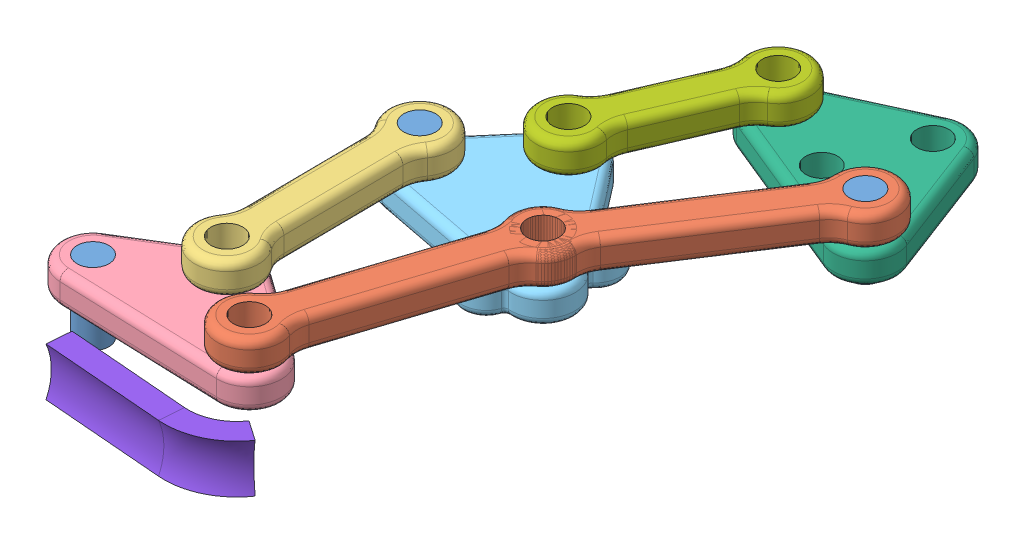
SolidWorks assembly Test, configuration Default. Lengths in mm.
Overall size (93.86 21.45 141.22).
11 component instances, 8 part files, 23 mates.
Components (placement in the parent):
- Pin-2: Pin [Default] at (17.2663 20.8923 103.6402) x (-0.850358 0 0.526205) z (-0.526205 0 -0.850358) size (6.6 14.85 6.6)
- Pin-5: Pin [Default] at (75.0993 20.8923 69.342) size (6.6 14.85 6.6)
- 7.3mmLink-1: 7.3mmLink [Default] at (52.0373 31.2673 104.85) x (0.544688 0 -0.838639) z (0.838639 0 0.544688) size (61.38 6.6 13.2)
- 6mmLink-3: 6mmLink [Default] at (17.5842 31.2673 138.9955) x (-0.008992 0 -0.99996) z (0.99996 0 -0.008992) size (53.43 6.6 13.2)
- 7.3mmLink-2: 7.3mmLink [Default] at (35.7914 31.2673 150.0215) x (0.30857 0 -0.951202) z (0.951202 0 0.30857) size (61.38 6.6 13.2)
- TriLink3-3: TriLink3 [Default] at (17.8182 24.6673 139.6408) x (0.852314 0 -0.52303) z (0.52303 0 0.852314) size (41.14 6.6 31.73)
- TriLink2-6: TriLink2 [Default] at (30.1841 24.6673 79.864) x (0.653306 0 -0.757094) z (0.757094 0 0.653306) size (35.81 6.6 41.11)
- TriLink1-5: TriLink1 [Default] at (68.8686 24.6673 41.0221) x (0.90935 0 -0.416033) z (0.416033 0 0.90935) size (37.33 6.6 37.28)
- Pin-6: Pin [Default] at (0.4822 14.2923 154.3938) x (0.997175 0 -0.075115) z (0.075115 0 0.997175) size (6.6 14.85 6.6)
- 5mmLink-4: 5mmLink [Default] at (33.0867 31.2673 83.4671) x (0.39569 0 -0.918384) z (0.918384 0 0.39569) size (46.2 6.6 13.2)
- Pad-1: Pad [Default] at (12.0164 27.9673 170.2645) x (0.996713 0 0.081009) z (-0.081009 0 0.996713) size (38.39 10 10)
Mates (geometry in assembly coordinates):
- Concentric9: concentric aligned: cylinder of Pin-5 through (75.0993 39.5673 69.342) axis (0 -1 0) radius 3.3; cylinder of 7.3mmLink-1 through (75.0993 39.5673 69.342) axis (0 -1 0) radius 3.3
- Coincident12: coincident aligned: plane of Pin-2 through (17.2663 39.5673 103.6402) normal (0 1 0); plane of 7.3mmLink-1 through (44.0533 39.5673 97.4525) normal (0 1 0)
- Concentric11: concentric aligned: cylinder of Pin-2 through (17.2663 39.5673 103.6402) axis (0 -1 0) radius 3.3; cylinder of 6mmLink-3 through (17.2663 39.5673 103.6402) axis (0 -1 0) radius 3.3
- Coincident13: coincident aligned: plane of Pin-2 through (17.2663 39.5673 103.6402) normal (0 1 0); plane of 6mmLink-3 through (6.8343 39.5673 136.2738) normal (0 1 0)
- Coincident16: coincident anti-aligned: plane of 7.3mmLink-2 through (26.1622 32.9673 144.9476) normal (0 -1 0); plane of TriLink3-3 through (0.4822 32.9673 154.3938) normal (0 1 0)
- Coincident23: coincident aligned: plane of Pin-5 through (75.0993 39.5673 69.342) normal (0 1 0); plane of 7.3mmLink-1 through (44.0533 39.5673 97.4525) normal (0 1 0)
- Coincident24: coincident anti-aligned: plane of 6mmLink-3 through (6.8343 32.9673 136.2738) normal (0 -1 0); plane of TriLink2-6 through (17.2663 32.9673 103.6402) normal (0 1 0)
- Concentric27: concentric aligned: cylinder of Pin-5 through (75.0993 39.5673 69.342) axis (0 -1 0) radius 3.3; cylinder of TriLink1-5 through (75.0993 32.9673 69.342) axis (0 -1 0) radius 3.3
- Coincident25: coincident anti-aligned: plane of 7.3mmLink-1 through (44.0533 32.9673 97.4525) normal (0 -1 0); plane of TriLink1-5 through (44.5617 32.9673 56.834) normal (0 1 0)
- Coincident27: coincident anti-aligned: plane of 7.3mmLink-2 through (26.1622 32.9673 144.9476) normal (0 -1 0); plane of TriLink2-6 through (17.2663 32.9673 103.6402) normal (0 1 0)
- Concentric29: concentric aligned: cylinder of TriLink3-3 through (0.4822 32.9673 154.3938) axis (0 -1 0) radius 3.3; cylinder of Pin-6 through (0.4822 32.9673 154.3938) axis (0 -1 0) radius 3.3
- Coincident31: coincident aligned: plane of TriLink3-3 through (0.4822 32.9673 154.3938) normal (0 1 0); plane of Pin-6 through (0.4822 32.9673 154.3938) normal (0 1 0)
- Concentric30: concentric aligned: cylinder of TriLink2-6 through (31.5039 32.9673 87.1407) axis (0 -1 0) radius 3.3; cylinder of 5mmLink-4 through (31.5039 39.5673 87.1407) axis (0 -1 0) radius 3.3
- Coincident32: coincident anti-aligned: plane of TriLink2-6 through (17.2663 32.9673 103.6402) normal (0 1 0); plane of 5mmLink-4 through (24.6991 32.9673 75.8298) normal (0 -1 0)
- Concentric32: concentric aligned: cylinder of 7.3mmLink-1 through (48.8563 39.5673 109.7477) axis (0 -1 0) radius 3.3; cylinder of 7.3mmLink-2 through (48.8563 39.5673 109.7477) axis (0 -1 0) radius 3.3
- Concentric33: concentric aligned: cylinder of 7.3mmLink-2 through (33.9894 39.5673 155.5766) axis (0 -1 0) radius 3.3; cylinder of TriLink3-3 through (33.9894 32.9673 155.5766) axis (0 -1 0) radius 3.3
- Concentric34: concentric aligned: cylinder of 6mmLink-3 through (17.6281 39.5673 143.8721) axis (0 -1 0) radius 3.3; cylinder of TriLink3-3 through (17.6281 32.9673 143.8721) axis (0 -1 0) radius 3.3
- Concentric35: concentric aligned: cylinder of Pin-2 through (17.2663 39.5673 103.6402) axis (0 -1 0) radius 3.3; cylinder of TriLink2-6 through (17.2663 32.9673 103.6402) axis (0 -1 0) radius 3.3
- Concentric36: concentric aligned: cylinder of 7.3mmLink-2 through (48.8563 39.5673 109.7477) axis (0 -1 0) radius 3.3; cylinder of TriLink2-6 through (48.8563 32.9673 109.7477) axis (0 -1 0) radius 3.3
- Coincident34: coincident anti-aligned: cylinder of TriLink1-5 through (44.5617 32.9673 56.834) axis (0 -1 0) radius 3.3; circle of 5mmLink-4
- Coincident35: coincident: plane of TriLink3-3 through (0.2494 32.9673 160.9897) normal (-0.035276 0 0.999378); plane of Pad-1 through (12.0164 32.9673 170.2645) normal (0.081009 0 -0.996713)
- Coincident36: coincident aligned: plane of TriLink3-3 through (0.4822 32.9673 154.3938) normal (0 1 0); plane of Pad-1 through (12.0164 32.9673 170.2645) normal (0 1 0)
- Concentric37: concentric: cylinder of TriLink3-3 through (33.9894 32.9673 155.5766) axis (0 -1 0) radius 6.6; cylinder of Pad-1 through (38.143 27.9673 162.355) axis (0 1 0) radius 10
